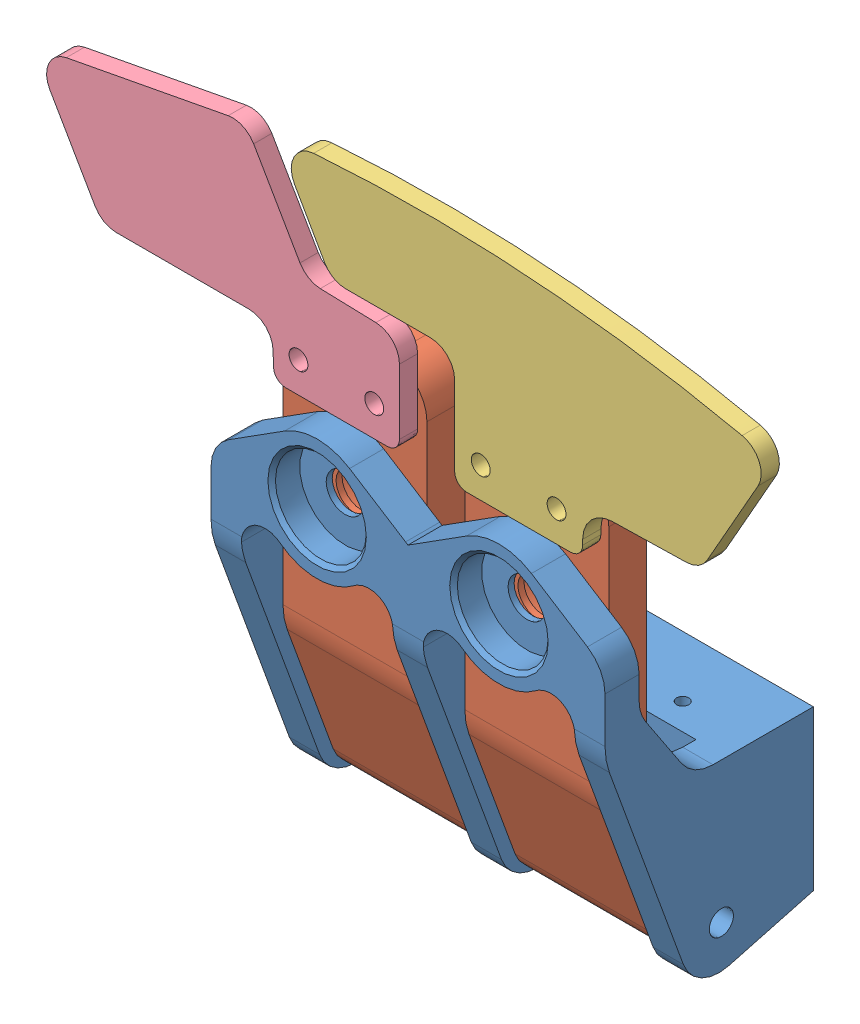
SolidWorks assembly double shifter assembly, configuration Default. Lengths in mm.
Overall size (94.31 80.4 27.5).
5 component instances, 4 part files, 11 mates.
Components (placement in the parent):
- double main body-1: double main body [Default] at (20.4834 22.0287 42.8183) size (52 49.55 27.5)
- Step_MS01_-_Shifter_Lever-1: Step_MS01_-_Shifter_Lever [Default] at (53.3293 63.2691 75.7552) size (19 58.15 15.35)
- Step_MS01_-_Shifter_Lever-2: Step_MS01_-_Shifter_Lever [Default] at (29.3293 63.2691 75.7552) size (19 58.15 15.35)
- middleLeftPaddle-1: middleLeftPaddle [Default] at (390.482 792.7724 106.6696) x (0 -1 0) z (0 0 -1) size (29.18 62.03 2.4)
- topLeftPaddle-1: topLeftPaddle [Default] at (397.4086 793.4705 106.6696) x (0 -1 0) z (0 0 -1) size (27.36 46.57 2.4)
Mates (geometry in assembly coordinates):
- Concentric1: concentric aligned: circle of double main body-1; circle of Step_MS01_-_Shifter_Lever-1
- Coincident1: coincident anti-aligned: plane of double main body-1 through (62.8293 49.6102 95.23) normal (-1 0 0); plane of Step_MS01_-_Shifter_Lever-1 through (62.8293 65.0006 93.2927) normal (1 0 0)
- Coincident2: coincident anti-aligned: plane of double main body-1 through (28.8293 74.4974 100.9696) normal (0 0 -1); plane of Step_MS01_-_Shifter_Lever-1 through (62.8293 70.8757 100.9696) normal (0 0 1)
- Concentric2: concentric aligned: circle of double main body-1; circle of Step_MS01_-_Shifter_Lever-2
- Coincident3: coincident anti-aligned: plane of double main body-1 through (38.8293 49.6102 95.23) normal (-1 0 0); plane of Step_MS01_-_Shifter_Lever-2 through (38.8293 65.0006 93.2927) normal (1 0 0)
- Coincident4: coincident anti-aligned: plane of double main body-1 through (28.8293 74.4974 100.9696) normal (0 0 -1); plane of Step_MS01_-_Shifter_Lever-2 through (38.8293 70.8757 100.9696) normal (0 0 1)
- Coincident5: coincident anti-aligned: plane of Step_MS01_-_Shifter_Lever-2 through (38.8293 70.8757 100.9696) normal (0 0 1); plane of middleLeftPaddle-1 through (40.8241 -81.9166 100.9696) normal (0 0 -1)
- Coincident6: coincident aligned: circle of Step_MS01_-_Shifter_Lever-1; circle of middleLeftPaddle-1
- Coincident8: coincident aligned: circle of Step_MS01_-_Shifter_Lever-1; circle of middleLeftPaddle-1
- Coincident9: coincident anti-aligned: plane of Step_MS01_-_Shifter_Lever-2 through (38.8293 70.8757 100.9696) normal (0 0 1); plane of topLeftPaddle-1 through (320.8099 654.6785 100.9696) normal (0 0 -1)
- Coincident14: coincident aligned: plane of middleLeftPaddle-1 through (44.88 86.0433 100.9696) normal (0 -1 0); plane of topLeftPaddle-1 through (21.0151 86.0433 100.9696) normal (0 -1 0)
